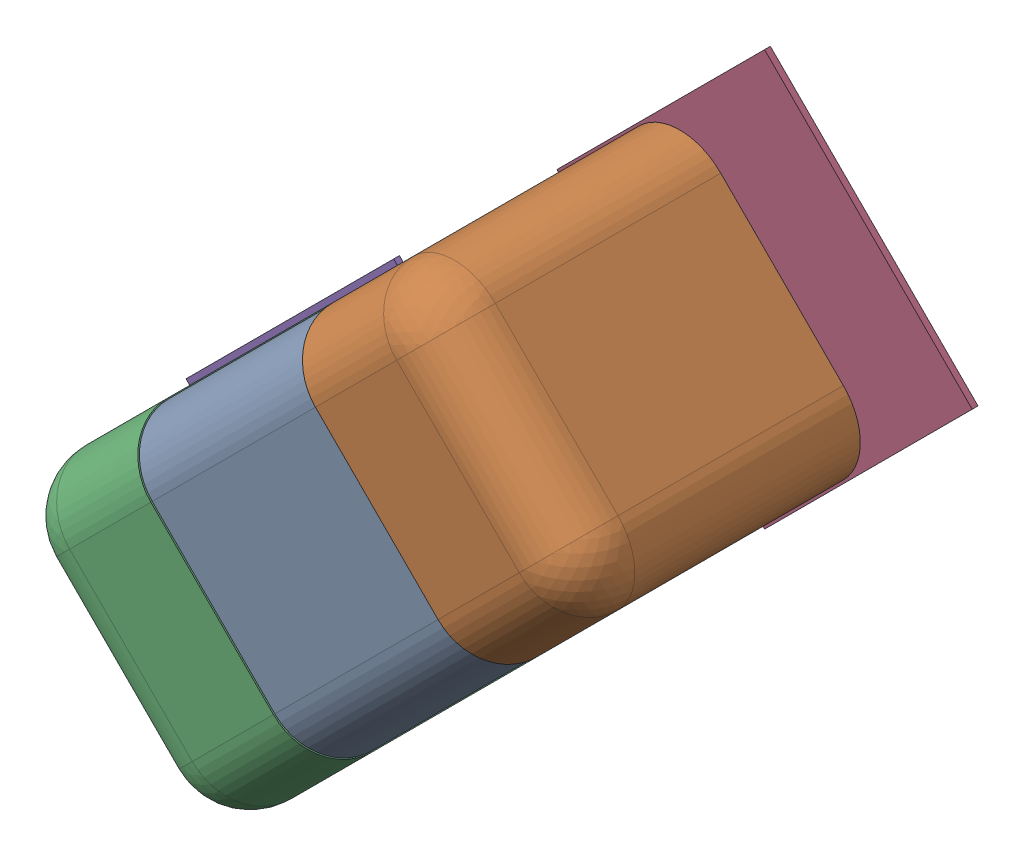
SolidWorks assembly C4, configuration Défaut. Lengths in mm.
Overall size (1.36 1.35 0.5).
8 component instances, 4 part files, 0 mates.
Components (placement in the parent):
- 7300435664-1: 7300435664 [Défaut] at (67.5887 -33.554 0) x (-0.707107 -0.707107 0) z (-0.707107 0.707107 0) size (1 0.5 0.5)
  - Open CASCADE STEP translator 7.5 2.451.1.1-1: Open CASCADE STEP translator 7.5 2.451.1.1 [Défaut] at origin size (0.4 0.5 0.5)
  - Open CASCADE STEP translator 7.5 2.451.1.2-1: Open CASCADE STEP translator 7.5 2.451.1.2 [Défaut] at origin size (0.3 0.5 0.5)
  - Open CASCADE STEP translator 7.5 2.451.1.3-1: Open CASCADE STEP translator 7.5 2.451.1.3 [Défaut] at origin size (0.3 0.5 0.5)
- 8260096304-1: 8260096304 [Défaut] at (67.912 -33.2306 0) size (0.72 0.72 0.01)
  - Extruded_694-1: Extruded_694 [Défaut] at origin size (0.72 0.72 0.01)
- 8260096304-2: 8260096304 [Défaut] at (67.2703 -33.865 0) size (0.72 0.72 0.01)
  - Extruded_694-1: Extruded_694 [Défaut] at origin size (0.72 0.72 0.01)
